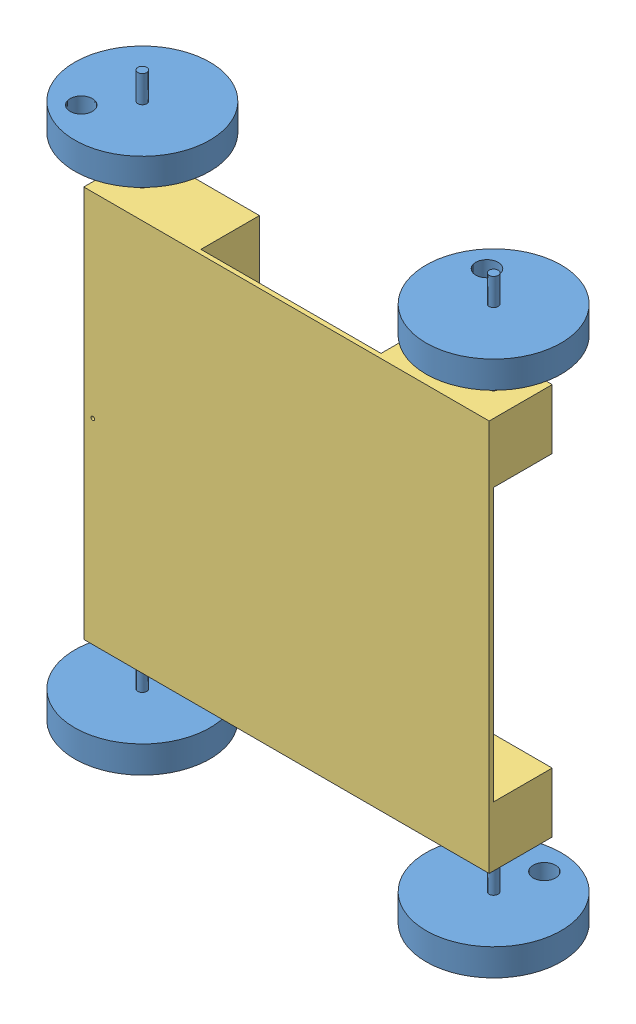
SolidWorks assembly lunc, configuration 默认. Lengths in mm.
Overall size (593.07 655 203.07).
9 component instances, 3 part files, 16 mates.
Components (placement in the parent):
- lun-5: lun [默认] at (167.0466 -264.3091 -75) x (-0.881339 0 0.472485) z (0 -1 0) size (150 150 90)
- zhou-6: zhou [默认] at (167.0466 -234.3091 -75) x (1 0 0) z (0 1 0) size (10 10 30)
- zhou-7: zhou [默认] at (-222.9534 -234.3091 -75) x (-0.133084 0 -0.991105) z (0 1 0) size (10 10 30)
- zhou-8: zhou [默认] at (-222.9534 210.6909 -75) x (1 0 0) z (0 1 0) size (10 10 30)
- zhou-9: zhou [默认] at (167.0466 210.6909 -75) x (1 0 0) z (0 1 0) size (10 10 30)
- lun-6: lun [默认] at (167.0466 300.6909 -75) x (0 0 1) z (0 -1 0) size (150 150 90)
- lun-7: lun [默认] at (-222.9534 -264.3091 -75) x (-0.881339 0 0.472485) z (0 -1 0) size (150 150 90)
- SIMPLE DIPAN-2: SIMPLE DIPAN [默认] at (-27.9534 3.1909 -40) x (-1 0 0) z (0 0 -1) size (450 435 70)
- lun-8: lun [默认] at (-222.9534 300.6909 -75) x (1 0 0) z (0 -1 0) size (150 150 90)
Mates (geometry in assembly coordinates):
- 重合24: coincident: plane of zhou-7 through (-222.9534 -234.3091 -75) normal (0 -1 0); plane of lun-7 through (-222.9534 -234.3091 -75) normal (0 1 0)
- 同心17: concentric: cylinder of zhou-7 through (-222.9534 -204.3091 -75) axis (0 -1 0) radius 5; cylinder of lun-7 through (-222.9534 -234.3091 -75) axis (0 -1 0) radius 5
- 重合25: coincident: plane of lun-5 through (167.0466 -234.3091 -75) normal (0 1 0); plane of zhou-6 through (167.0466 -234.3091 -75) normal (0 -1 0)
- 同心18: concentric: cylinder of lun-5 through (167.0466 -234.3091 -75) axis (0 -1 0) radius 5; cylinder of zhou-6 through (167.0466 -204.3091 -75) axis (0 -1 0) radius 5
- 重合26: coincident: plane of zhou-6 through (167.0466 -204.3091 -75) normal (0 1 0); plane of SIMPLE DIPAN-2 through (167.0466 -204.3091 -75) normal (0 -1 0)
- 同心19: concentric: cylinder of zhou-6 through (167.0466 -204.3091 -75) axis (0 -1 0) radius 5; cylinder of SIMPLE DIPAN-2 through (167.0466 -204.3091 -75) axis (0 -1 0) radius 5
- 重合27: coincident: plane of zhou-7 through (-222.9534 -204.3091 -75) normal (0 1 0); plane of SIMPLE DIPAN-2 through (-222.9534 -204.3091 -75) normal (0 -1 0)
- 同心20: concentric: cylinder of zhou-7 through (-222.9534 -204.3091 -75) axis (0 -1 0) radius 5; cylinder of SIMPLE DIPAN-2 through (-222.9534 -204.3091 -75) axis (0 -1 0) radius 5
- 重合28: coincident: plane of zhou-8 through (-222.9534 210.6909 -75) normal (0 -1 0); plane of SIMPLE DIPAN-2 through (-222.9534 210.6909 -75) normal (0 1 0)
- 同心21: concentric: cylinder of zhou-8 through (-222.9534 240.6909 -75) axis (0 -1 0) radius 5; cylinder of SIMPLE DIPAN-2 through (-222.9534 210.6909 -75) axis (0 1 0) radius 5
- 重合29: coincident: plane of zhou-8 through (-222.9534 240.6909 -75) normal (0 1 0); plane of lun-8 through (-222.9534 240.6909 -75) normal (0 -1 0)
- 同心22: concentric: cylinder of zhou-8 through (-222.9534 240.6909 -75) axis (0 -1 0) radius 5; cylinder of lun-8 through (-222.9534 330.6909 -75) axis (0 -1 0) radius 5
- 重合30: coincident: plane of zhou-9 through (167.0466 210.6909 -75) normal (0 -1 0); plane of SIMPLE DIPAN-2 through (167.0466 210.6909 -75) normal (0 1 0)
- 同心23: concentric: cylinder of zhou-9 through (167.0466 240.6909 -75) axis (0 -1 0) radius 5; cylinder of SIMPLE DIPAN-2 through (167.0466 210.6909 -75) axis (0 1 0) radius 5
- 重合31: coincident: plane of zhou-9 through (167.0466 240.6909 -75) normal (0 1 0); plane of lun-6 through (167.0466 240.6909 -75) normal (0 -1 0)
- 同心24: concentric: cylinder of zhou-9 through (167.0466 240.6909 -75) axis (0 -1 0) radius 5; cylinder of lun-6 through (167.0466 330.6909 -75) axis (0 -1 0) radius 5
